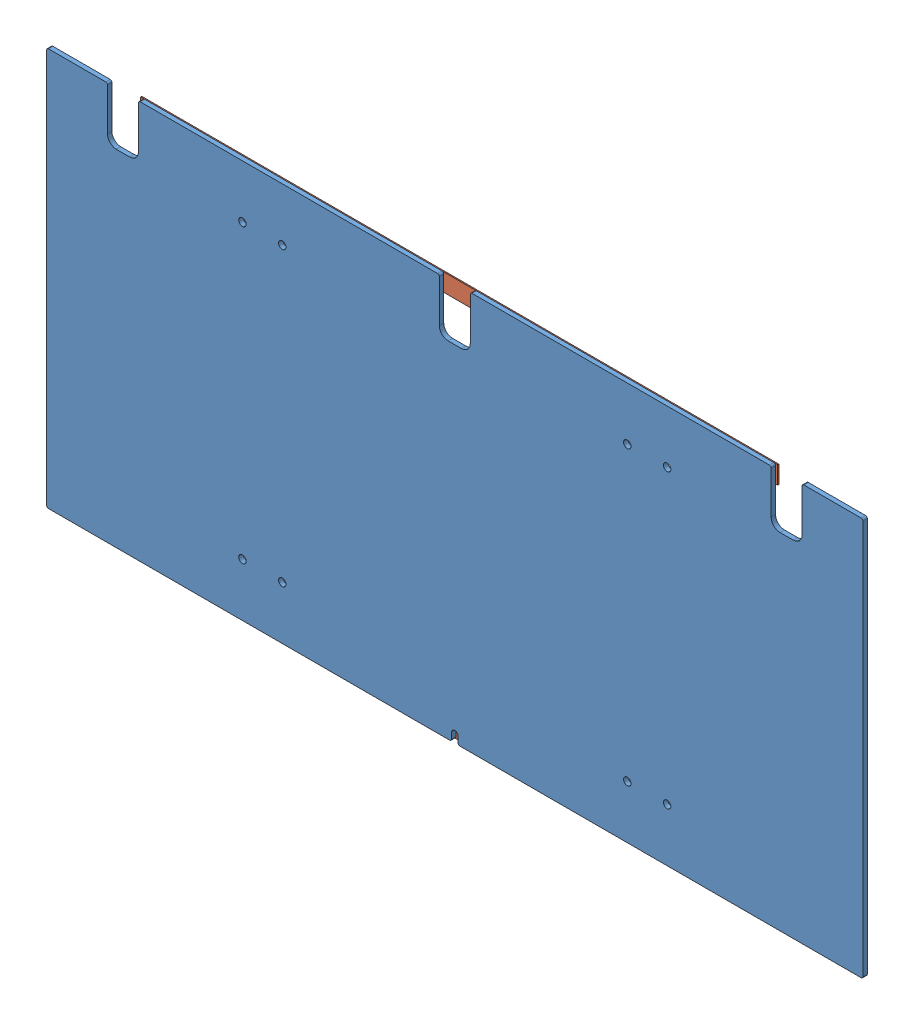
SolidWorks assembly GE-22345, configuration Default. Lengths in mm.
Overall size (1171.58 571.5 7.94).
3 component instances, 2 part files, 9 mates.
Components (placement in the parent):
- GE-22344-1: GE-22344 [Default] at origin size (1171.58 571.5 6.35)
- Loop_1_36-3: Loop_1_36 [Default] at (-457.2 546.1 -1.5875) x (1 0 0) z (0 -1 0) size (914.4 1.59 25.4)
- Loop_1_36-2: Loop_1_36 [Default] at (-457.2 0 -1.5875) x (1 0 0) z (0 -1 0) size (914.4 1.59 25.4)
Mates (geometry in assembly coordinates):
- Coincident1: coincident anti-aligned: plane of GE-22344-1 through (0 0 0) normal (0 0 -1); plane of Hook_1_36-1 through (-457.2 546.1 0) normal (0 0 1)
- Coincident2: coincident aligned: plane of fenderPlastic_mockV2-1 through (-585.7875 571.5 6.35) normal (0 1 0); plane of Hook_1_36-1 through (-457.2 571.5 0) normal (0 1 0)
- Width1: width aligned: plane of Hook_1_36-1 through (457.2 546.1 0) normal (1 0 0); plane of Hook_1_36-1 through (-457.2 546.1 0) normal (-1 0 0); plane of GE-22344-1 through (585.7875 0 6.35) normal (1 0 0); plane of GE-22344-1 through (-585.7875 0 6.35) normal (-1 0 0)
- Coincident3: coincident anti-aligned: plane of GE-22344-1 through (0 0 0) normal (0 0 -1); plane of Hook_1_36-2 through (-457.2 0 0) normal (0 0 1)
- Coincident5: coincident aligned: plane of Hook_1_36-1 through (-457.2 546.1 0) normal (-1 0 0); plane of Hook_1_36-2 through (-457.2 0 0) normal (-1 0 0)
- Coincident6: coincident aligned: plane of fenderPlastic_mockV2-1 through (-585.7875 0 6.35) normal (0 -1 0); plane of Hook_1_36-2 through (-457.2 0 0) normal (0 -1 0)
- Coincident7: coincident aligned: plane of GE-22344-1 through (0 0 0) normal (0 0 1)
- Coincident8: coincident aligned: plane of GE-22344-1 through (0 0 0) normal (0 1 0)
- Coincident9: coincident aligned: plane of GE-22344-1 through (0 0 0) normal (1 0 0)
